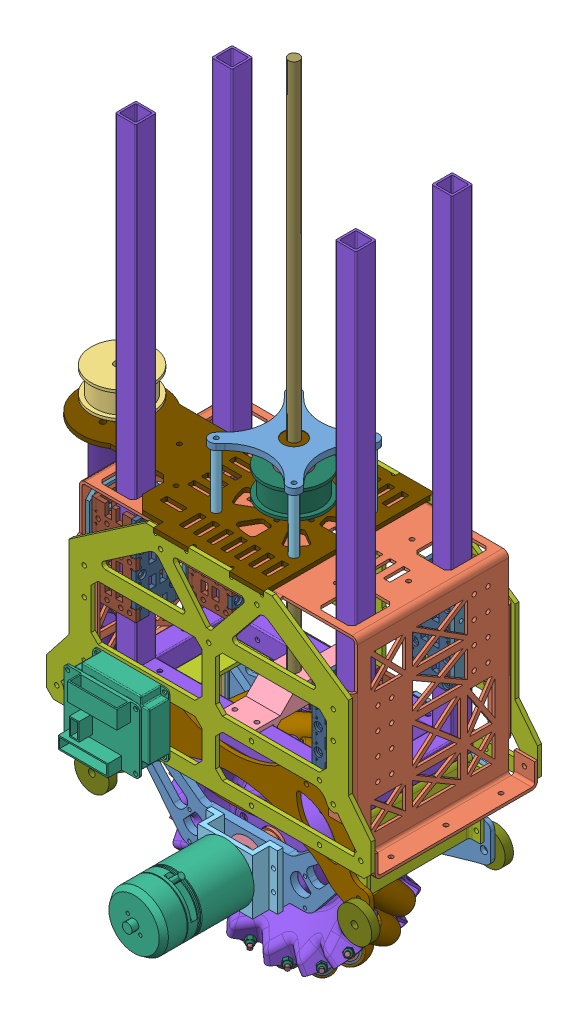
SolidWorks assembly 轮子模块 the other side, configuration 默认. Lengths in mm.
Overall size (273 598.21 183.3).
223 component instances, 37 part files, 118 mates.
Components (placement in the parent):
- 轮子固定铝件-1: 轮子固定铝件 [默认] at (-59.2295 -8.2139 167) size (170 67.5 6)
- 悬挂轮轴-3510（8.0）-1: 悬挂轮轴-3510（8.0） [默认] at (-59.2295 -8.2139 228.5) x (-0.707107 -0.707107 0) z (0 0 -1) size (54 54 80)
- 轮子固定铝件-2: 轮子固定铝件 [默认] at (-59.2295 -8.2139 235) x (-1 0 0) z (0 0 -1) size (170 67.5 6)
- 轮子固定片 连接件-1: 轮子固定片 连接件 [默认] at (104.7705 16.7861 201) x (1 0 0) z (0 1 0) size (7 58 25)
- 法兰轴承15-28-7 （00）-3: 法兰轴承15-28-7 （00） [默认] at (-59.2295 -8.2139 234.5) x (-0.923728 -0.383049 0) z (0 0 -1) size (30.5 30.5 7)
- 法兰轴承15-28-7 （00）-4: 法兰轴承15-28-7 （00） [默认] at (-59.2295 -8.2139 167.5) size (30.5 30.5 7)
- 轮子固定片 连接件-2: 轮子固定片 连接件 [默认] at (-223.2295 16.7861 201) x (-1 0 0) z (0 1 0) size (7 58 25)
- 悬挂-电机架（3510-8.0）-1: 悬挂-电机架（3510-8.0） [默认] at (-59.2295 -28.2139 262.3988) x (1 0 0) z (0 1 0) size (52 16 40)
- 3510无刷电机带减速箱（00）-1: 3510无刷电机带减速箱（00） [默认] at (-59.2295 -8.2139 278.6) x (-0.707107 0.707107 0) z (0.707107 0.707107 0) size (42 98.3 47)
- 轮子固定钣金-1: 轮子固定钣金 [默认] at (-59.2295 61.7861 158.5) size (191 52.5 85)
- 伸缩框架-2.0-（3510）  轻量化（8.0）-1: 伸缩框架-2.0-（3510）  轻量化（8.0） [默认<按加工>] at (-59.2295 71.7861 201) size (193.2 417.5 85)
- 加固碳板-1: 加固碳板 [默认] at (-59.2295 45.5361 243.5) size (201 81.5 3)
- 碳板滑车-1: 碳板滑车 [默认] at (49.0727 115.5126 186.5) size (32 64 32)
  - 碳板长滑车拼接板1-1: 碳板长滑车拼接板1 [默认] at (-28.3022 -33.7153 62.5) size (32 64 3)
  - 碳板长滑车拼接板2-1: 碳板长滑车拼接板2 [默认] at (-12.3022 30.2847 49.5) x (0 0 -1) z (-1 0 0) size (32 64 3)
  - 碳板长滑车拼接板1-2: 碳板长滑车拼接板1 [默认] at (-41.3022 30.2847 49.5) x (0 0 -1) z (-1 0 0) size (32 64 3)
  - 碳板长滑车拼接板2-2: 碳板长滑车拼接板2 [默认] at (-28.3022 -33.7153 33.5) size (32 64 3)
- 碳板滑车-2: 碳板滑车 [默认] at (49.0727 150.5126 116.5) size (32 64 32)
  - 碳板长滑车拼接板1-1: 碳板长滑车拼接板1 [默认] at (-28.3022 -33.7153 62.5) size (32 64 3)
  - 碳板长滑车拼接板2-1: 碳板长滑车拼接板2 [默认] at (-12.3022 30.2847 49.5) x (0 0 -1) z (-1 0 0) size (32 64 3)
  - 碳板长滑车拼接板1-2: 碳板长滑车拼接板1 [默认] at (-41.3022 30.2847 49.5) x (0 0 -1) z (-1 0 0) size (32 64 3)
  - 碳板长滑车拼接板2-2: 碳板长滑车拼接板2 [默认] at (-28.3022 -33.7153 33.5) size (32 64 3)
- 碳板滑车-3: 碳板滑车 [默认] at (-167.5318 115.5126 215.5) x (-1 0 0) z (0 0 -1) size (32 64 32)
  - 碳板长滑车拼接板1-1: 碳板长滑车拼接板1 [默认] at (-28.3022 -33.7153 62.5) size (32 64 3)
  - 碳板长滑车拼接板2-1: 碳板长滑车拼接板2 [默认] at (-12.3022 30.2847 49.5) x (0 0 -1) z (-1 0 0) size (32 64 3)
  - 碳板长滑车拼接板1-2: 碳板长滑车拼接板1 [默认] at (-41.3022 30.2847 49.5) x (0 0 -1) z (-1 0 0) size (32 64 3)
  - 碳板长滑车拼接板2-2: 碳板长滑车拼接板2 [默认] at (-28.3022 -33.7153 33.5) size (32 64 3)
- 碳板滑车-4: 碳板滑车 [默认] at (-188.7295 147.0821 264.3022) x (0 0 1) z (1 0 0) size (32 64 32)
  - 碳板长滑车拼接板1-1: 碳板长滑车拼接板1 [默认] at (-28.3022 -33.7153 62.5) size (32 64 3)
  - 碳板长滑车拼接板2-1: 碳板长滑车拼接板2 [默认] at (-12.3022 30.2847 49.5) x (0 0 -1) z (-1 0 0) size (32 64 3)
  - 碳板长滑车拼接板1-2: 碳板长滑车拼接板1 [默认] at (-41.3022 30.2847 49.5) x (0 0 -1) z (-1 0 0) size (32 64 3)
  - 碳板长滑车拼接板2-2: 碳板长滑车拼接板2 [默认] at (-28.3022 -33.7153 33.5) size (32 64 3)
- T8-300丝杆-1: T8-300丝杆 [默认] at (-59.2295 79.2861 201) x (-0.352036 0 -0.935986) z (0.935986 0 -0.352036) size (8 400 8)
- CBHG丝杆螺母-内8mm-1: CBHG丝杆螺母-内8mm [默认] at (-59.2295 226.2973 201) x (-0.096242 0 -0.995358) z (-0.995358 0 0.096242) size (22 16.5 22)
- 碳板垫片-1: 碳板垫片 [默认] at (36.7705 117.7973 236) x (0 0 -1) z (1 0 0) size (35 60 3)
- 碳板垫片-2: 碳板垫片 [默认] at (-155.2295 152.7973 236) x (0 0 1) z (-1 0 0) size (35 60 3)
- 碳板垫片-3: 碳板垫片 [默认] at (-155.2295 117.7973 166) x (0 0 1) z (-1 0 0) size (35 60 3)
- 碳板垫片-4: 碳板垫片 [默认] at (36.7705 152.7973 166) x (0 0 -1) z (1 0 0) size (35 60 3)
- M5 25齿 同步轮-1: M5 25齿 同步轮 [默认] at (-59.2295 221.2973 201) x (0.096242 0 0.995358) z (0.995358 0 -0.096242) size (45 20 45)
- 内径10外20厚5-1: 内径10外20厚5 [默认] at (-59.2295 203.2973 201) x (0.98727 0 0.159053) z (-0.159053 0 0.98727) size (19 5 19)
- 毒升电机-1: 毒升电机 [默认] at (-184.2295 143.6973 201) x (1 0 0) z (0 1 0) size (35 42.5 158.6)
- 688 ZZ 轴承-1: 688 ZZ 轴承 [默认] at (-59.2295 239.2973 201) x (-0.805456 0 -0.592655) z (-0.592655 0 0.805456) size (18 5 18)
- 同步带限位铝件3-1: 同步带限位铝件3 [默认] at (-59.2295 240.2973 201) x (0 0 1) z (1 0 0) size (66.57 4.5 66.57)
- 轮子模块定位固定钣金-1: 轮子模块定位固定钣金 [默认] at (-59.2295 189.2973 146) size (236 142 118)
- M5 25齿 同步轮（电机用）-1: M5 25齿 同步轮（电机用） [默认] at (-184.2295 205.2973 201) x (-1 0 0) z (0 0 -1) size (45 20 45)
- 丝杆末端定位铝件-1: 丝杆末端定位铝件 [默认] at (-46.7295 82.2861 201) x (0 0 1) z (-1 0 0) size (85 25 25)
- 41.5mm铝棒-1: 41.5mm铝棒 [默认] at (-30.9453 194.2973 229.2843) x (-0.695799 0 0.718237) z (-0.718237 0 -0.695799) size (6 41 6)
- 41.5mm铝棒-2: 41.5mm铝棒 [默认] at (-87.5138 194.2973 172.7157) size (6 41 6)
- 41.5mm铝棒-3: 41.5mm铝棒 [默认] at (-87.5138 194.2973 229.2843) size (6 41 6)
- 41.5mm铝棒-4: 41.5mm铝棒 [默认] at (-30.9453 194.2973 172.7157) x (0.902918 0 -0.429812) z (0.429812 0 0.902918) size (6 41 6)
- 毒升电机电调-1: 毒升电机电调 [默认] at (-115.0295 75.1473 263) x (-1 0 0) z (0 0 1) size (55 46.3 32)
- 钣金加固碳板侧面-1: 钣金加固碳板侧面 [默认] at (-59.2295 183.2973 260) size (236 144.5 3)
- 钣金加固碳板侧面-2: 钣金加固碳板侧面 [默认] at (-59.2295 183.2973 139) size (236 144.5 3)
- 麦轮组装左-1: 麦轮组装左 [默认] at (-42.3506 -22.7788 70.6482) x (0.935906 -0.35225 0) z (0 0 1) size (168 168 53.18)
  - 麦轮钣金-1: 麦轮钣金 [默认] at (-20.9276 7.6858 132.4522) size (142.88 142.88 24.05)
  - 麦轮钣金-2: 麦轮钣金 [默认] at (-20.9276 7.6858 129.2518) x (-0.980785 -0.19509 0) z (0 0 -1) size (142.88 142.88 24.05)
  - 滚花橡胶轮组装-1: 滚花橡胶轮组装 [默认] at (60.4121 -1.9858 154.8754) x (0.932849 -0.320965 -0.163627) z (-0.338043 -0.622763 -0.705615) size (18.5 18.5 53)
    - 滚花橡胶轮外-1: 滚花橡胶轮外 [默认] at (-9.896 1.7835 38.5971) size (18.5 18.5 38)
    - 滚花铝柱-1: 滚花铝柱 [默认] at (-9.896 1.7835 38) x (0.787441 0.61639 0) z (-0.61639 0.787441 0) size (13 38 13)
    - 轴承5X10X4-1: 轴承5X10X4 [默认] at (-9.896 1.7835 55) x (0.442498 0.896769 0) z (-0.896769 0.442498 0) size (10 4 10)
    - 轴承5X10X4-2: 轴承5X10X4 [默认] at (-9.896 1.7835 21) x (0.442498 0.896769 0) z (-0.896769 0.442498 0) size (10 4 10)
    - 铜管3X5-1: 铜管3X5 [默认] at (-9.896 1.7835 38) x (0.823254 0.567673 0) z (-0.567673 0.823254 0) size (5 38 5)
    - 螺丝-1: 螺丝 [默认] at (-9.896 1.7835 59.6) x (-0.462621 0.886556 0) z (0 0 1) size (5.5 5.5 53)
    - 垫片-1: 垫片 [默认] at (-9.896 1.7835 57) x (1 0 0) z (0 -1 0) size (7 0.8 7)
    - 垫片-2: 垫片 [默认] at (-9.896 1.7835 19) x (0.746862 -0.664979 0) z (0.664979 0.746862 0) size (7 0.8 7)
    - 螺母-1: 螺母 [默认] at (-9.896 1.7835 16.2) x (-0.766894 0.641774 0) z (0 0 -1) size (6.35 5.5 4.25)
  - 滚花橡胶轮组装-2: 滚花橡胶轮组装 [默认] at (57.9216 29.8777 154.8754) x (0.984668 0.060453 -0.163627) z (-0.073989 -0.704722 -0.705615) size (18.5 18.5 53)
    - 滚花橡胶轮外-1: 滚花橡胶轮外 [默认] at (-9.896 1.7835 38.5971) size (18.5 18.5 38)
    - 滚花铝柱-1: 滚花铝柱 [默认] at (-9.896 1.7835 38) x (0.787441 0.61639 0) z (-0.61639 0.787441 0) size (13 38 13)
    - 轴承5X10X4-1: 轴承5X10X4 [默认] at (-9.896 1.7835 55) x (0.442498 0.896769 0) z (-0.896769 0.442498 0) size (10 4 10)
    - 轴承5X10X4-2: 轴承5X10X4 [默认] at (-9.896 1.7835 21) x (0.442498 0.896769 0) z (-0.896769 0.442498 0) size (10 4 10)
    - 铜管3X5-1: 铜管3X5 [默认] at (-9.896 1.7835 38) x (0.823254 0.567673 0) z (-0.567673 0.823254 0) size (5 38 5)
    - 螺丝-1: 螺丝 [默认] at (-9.896 1.7835 59.6) x (-0.462621 0.886556 0) z (0 0 1) size (5.5 5.5 53)
    - 垫片-1: 垫片 [默认] at (-9.896 1.7835 57) x (1 0 0) z (0 -1 0) size (7 0.8 7)
    - 垫片-2: 垫片 [默认] at (-9.896 1.7835 19) x (0.746862 -0.664979 0) z (0.664979 0.746862 0) size (7 0.8 7)
    - 螺母-1: 螺母 [默认] at (-9.896 1.7835 16.2) x (-0.766894 0.641774 0) z (0 0 -1) size (6.35 5.5 4.25)
  - 滚花橡胶轮组装-3: 滚花橡胶轮组装 [默认] at (43.4271 58.3628 154.8754) x (0.88658 0.432668 -0.163627) z (0.201328 -0.679392 -0.705615) size (18.5 18.5 53)
    - 滚花橡胶轮外-1: 滚花橡胶轮外 [默认] at (-9.896 1.7835 38.5971) size (18.5 18.5 38)
    - 滚花铝柱-1: 滚花铝柱 [默认] at (-9.896 1.7835 38) x (0.787441 0.61639 0) z (-0.61639 0.787441 0) size (13 38 13)
    - 轴承5X10X4-1: 轴承5X10X4 [默认] at (-9.896 1.7835 55) x (0.442498 0.896769 0) z (-0.896769 0.442498 0) size (10 4 10)
    - 轴承5X10X4-2: 轴承5X10X4 [默认] at (-9.896 1.7835 21) x (0.442498 0.896769 0) z (-0.896769 0.442498 0) size (10 4 10)
    - 铜管3X5-1: 铜管3X5 [默认] at (-9.896 1.7835 38) x (0.823254 0.567673 0) z (-0.567673 0.823254 0) size (5 38 5)
    - 螺丝-1: 螺丝 [默认] at (-9.896 1.7835 59.6) x (-0.462621 0.886556 0) z (0 0 1) size (5.5 5.5 53)
    - 垫片-1: 垫片 [默认] at (-9.896 1.7835 57) x (1 0 0) z (0 -1 0) size (7 0.8 7)
    - 垫片-2: 垫片 [默认] at (-9.896 1.7835 19) x (0.746862 -0.664979 0) z (0.664979 0.746862 0) size (7 0.8 7)
    - 螺母-1: 螺母 [默认] at (-9.896 1.7835 16.2) x (-0.766894 0.641774 0) z (0 0 -1) size (6.35 5.5 4.25)
  - 滚花橡胶轮组装-4: 滚花橡胶轮组装 [默认] at (19.1352 79.1327 154.8754) x (0.653519 0.739013 -0.163627) z (0.445995 -0.550632 -0.705615) size (18.5 18.5 53)
    - 滚花橡胶轮外-1: 滚花橡胶轮外 [默认] at (-9.896 1.7835 38.5971) size (18.5 18.5 38)
    - 滚花铝柱-1: 滚花铝柱 [默认] at (-9.896 1.7835 38) x (0.787441 0.61639 0) z (-0.61639 0.787441 0) size (13 38 13)
    - 轴承5X10X4-1: 轴承5X10X4 [默认] at (-9.896 1.7835 55) x (0.442498 0.896769 0) z (-0.896769 0.442498 0) size (10 4 10)
    - 轴承5X10X4-2: 轴承5X10X4 [默认] at (-9.896 1.7835 21) x (0.442498 0.896769 0) z (-0.896769 0.442498 0) size (10 4 10)
    - 铜管3X5-1: 铜管3X5 [默认] at (-9.896 1.7835 38) x (0.823254 0.567673 0) z (-0.567673 0.823254 0) size (5 38 5)
    - 螺丝-1: 螺丝 [默认] at (-9.896 1.7835 59.6) x (-0.462621 0.886556 0) z (0 0 1) size (5.5 5.5 53)
    - 垫片-1: 垫片 [默认] at (-9.896 1.7835 57) x (1 0 0) z (0 -1 0) size (7 0.8 7)
    - 垫片-2: 垫片 [默认] at (-9.896 1.7835 19) x (0.746862 -0.664979 0) z (0.664979 0.746862 0) size (7 0.8 7)
    - 螺母-1: 螺母 [默认] at (-9.896 1.7835 16.2) x (-0.766894 0.641774 0) z (0 0 -1) size (6.35 5.5 4.25)
  - 滚花橡胶轮组装-5: 滚花橡胶轮组装 [默认] at (-11.256 89.0255 154.8754) x (0.320965 0.932849 -0.163627) z (0.622763 -0.338043 -0.705615) size (18.5 18.5 53)
    - 滚花橡胶轮外-1: 滚花橡胶轮外 [默认] at (-9.896 1.7835 38.5971) size (18.5 18.5 38)
    - 滚花铝柱-1: 滚花铝柱 [默认] at (-9.896 1.7835 38) x (0.787441 0.61639 0) z (-0.61639 0.787441 0) size (13 38 13)
    - 轴承5X10X4-1: 轴承5X10X4 [默认] at (-9.896 1.7835 55) x (0.442498 0.896769 0) z (-0.896769 0.442498 0) size (10 4 10)
    - 轴承5X10X4-2: 轴承5X10X4 [默认] at (-9.896 1.7835 21) x (0.442498 0.896769 0) z (-0.896769 0.442498 0) size (10 4 10)
    - 铜管3X5-1: 铜管3X5 [默认] at (-9.896 1.7835 38) x (0.823254 0.567673 0) z (-0.567673 0.823254 0) size (5 38 5)
    - 螺丝-1: 螺丝 [默认] at (-9.896 1.7835 59.6) x (-0.462621 0.886556 0) z (0 0 1) size (5.5 5.5 53)
    - 垫片-1: 垫片 [默认] at (-9.896 1.7835 57) x (1 0 0) z (0 -1 0) size (7 0.8 7)
    - 垫片-2: 垫片 [默认] at (-9.896 1.7835 19) x (0.746862 -0.664979 0) z (0.664979 0.746862 0) size (7 0.8 7)
    - 螺母-1: 螺母 [默认] at (-9.896 1.7835 16.2) x (-0.766894 0.641774 0) z (0 0 -1) size (6.35 5.5 4.25)
  - 滚花橡胶轮组装-6: 滚花橡胶轮组装 [默认] at (-43.1195 86.535 154.8754) x (-0.060453 0.984668 -0.163627) z (0.704722 -0.073989 -0.705615) size (18.5 18.5 53)
    - 滚花橡胶轮外-1: 滚花橡胶轮外 [默认] at (-9.896 1.7835 38.5971) size (18.5 18.5 38)
    - 滚花铝柱-1: 滚花铝柱 [默认] at (-9.896 1.7835 38) x (0.787441 0.61639 0) z (-0.61639 0.787441 0) size (13 38 13)
    - 轴承5X10X4-1: 轴承5X10X4 [默认] at (-9.896 1.7835 55) x (0.442498 0.896769 0) z (-0.896769 0.442498 0) size (10 4 10)
    - 轴承5X10X4-2: 轴承5X10X4 [默认] at (-9.896 1.7835 21) x (0.442498 0.896769 0) z (-0.896769 0.442498 0) size (10 4 10)
    - 铜管3X5-1: 铜管3X5 [默认] at (-9.896 1.7835 38) x (0.823254 0.567673 0) z (-0.567673 0.823254 0) size (5 38 5)
    - 螺丝-1: 螺丝 [默认] at (-9.896 1.7835 59.6) x (-0.462621 0.886556 0) z (0 0 1) size (5.5 5.5 53)
    - 垫片-1: 垫片 [默认] at (-9.896 1.7835 57) x (1 0 0) z (0 -1 0) size (7 0.8 7)
    - 垫片-2: 垫片 [默认] at (-9.896 1.7835 19) x (0.746862 -0.664979 0) z (0.664979 0.746862 0) size (7 0.8 7)
    - 螺母-1: 螺母 [默认] at (-9.896 1.7835 16.2) x (-0.766894 0.641774 0) z (0 0 -1) size (6.35 5.5 4.25)
  - 滚花橡胶轮组装-7: 滚花橡胶轮组装 [默认] at (-71.6045 72.0405 154.8754) x (-0.432668 0.88658 -0.163627) z (0.679392 0.201328 -0.705615) size (18.5 18.5 53)
    - 滚花橡胶轮外-1: 滚花橡胶轮外 [默认] at (-9.896 1.7835 38.5971) size (18.5 18.5 38)
    - 滚花铝柱-1: 滚花铝柱 [默认] at (-9.896 1.7835 38) x (0.787441 0.61639 0) z (-0.61639 0.787441 0) size (13 38 13)
    - 轴承5X10X4-1: 轴承5X10X4 [默认] at (-9.896 1.7835 55) x (0.442498 0.896769 0) z (-0.896769 0.442498 0) size (10 4 10)
    - 轴承5X10X4-2: 轴承5X10X4 [默认] at (-9.896 1.7835 21) x (0.442498 0.896769 0) z (-0.896769 0.442498 0) size (10 4 10)
    - 铜管3X5-1: 铜管3X5 [默认] at (-9.896 1.7835 38) x (0.823254 0.567673 0) z (-0.567673 0.823254 0) size (5 38 5)
    - 螺丝-1: 螺丝 [默认] at (-9.896 1.7835 59.6) x (-0.462621 0.886556 0) z (0 0 1) size (5.5 5.5 53)
    - 垫片-1: 垫片 [默认] at (-9.896 1.7835 57) x (1 0 0) z (0 -1 0) size (7 0.8 7)
    - 垫片-2: 垫片 [默认] at (-9.896 1.7835 19) x (0.746862 -0.664979 0) z (0.664979 0.746862 0) size (7 0.8 7)
    - 螺母-1: 螺母 [默认] at (-9.896 1.7835 16.2) x (-0.766894 0.641774 0) z (0 0 -1) size (6.35 5.5 4.25)
  - 滚花橡胶轮组装-8: 滚花橡胶轮组装 [默认] at (-92.3745 47.7486 154.8754) x (-0.739013 0.653519 -0.163627) z (0.550632 0.445995 -0.705615) size (18.5 18.5 53)
    - 滚花橡胶轮外-1: 滚花橡胶轮外 [默认] at (-9.896 1.7835 38.5971) size (18.5 18.5 38)
    - 滚花铝柱-1: 滚花铝柱 [默认] at (-9.896 1.7835 38) x (0.787441 0.61639 0) z (-0.61639 0.787441 0) size (13 38 13)
    - 轴承5X10X4-1: 轴承5X10X4 [默认] at (-9.896 1.7835 55) x (0.442498 0.896769 0) z (-0.896769 0.442498 0) size (10 4 10)
    - 轴承5X10X4-2: 轴承5X10X4 [默认] at (-9.896 1.7835 21) x (0.442498 0.896769 0) z (-0.896769 0.442498 0) size (10 4 10)
    - 铜管3X5-1: 铜管3X5 [默认] at (-9.896 1.7835 38) x (0.823254 0.567673 0) z (-0.567673 0.823254 0) size (5 38 5)
    - 螺丝-1: 螺丝 [默认] at (-9.896 1.7835 59.6) x (-0.462621 0.886556 0) z (0 0 1) size (5.5 5.5 53)
    - 垫片-1: 垫片 [默认] at (-9.896 1.7835 57) x (1 0 0) z (0 -1 0) size (7 0.8 7)
    - 垫片-2: 垫片 [默认] at (-9.896 1.7835 19) x (0.746862 -0.664979 0) z (0.664979 0.746862 0) size (7 0.8 7)
    - 螺母-1: 螺母 [默认] at (-9.896 1.7835 16.2) x (-0.766894 0.641774 0) z (0 0 -1) size (6.35 5.5 4.25)
  - 滚花橡胶轮组装-9: 滚花橡胶轮组装 [默认] at (-102.2673 17.3574 154.8754) x (-0.932849 0.320965 -0.163627) z (0.338043 0.622763 -0.705615) size (18.5 18.5 53)
    - 滚花橡胶轮外-1: 滚花橡胶轮外 [默认] at (-9.896 1.7835 38.5971) size (18.5 18.5 38)
    - 滚花铝柱-1: 滚花铝柱 [默认] at (-9.896 1.7835 38) x (0.787441 0.61639 0) z (-0.61639 0.787441 0) size (13 38 13)
    - 轴承5X10X4-1: 轴承5X10X4 [默认] at (-9.896 1.7835 55) x (0.442498 0.896769 0) z (-0.896769 0.442498 0) size (10 4 10)
    - 轴承5X10X4-2: 轴承5X10X4 [默认] at (-9.896 1.7835 21) x (0.442498 0.896769 0) z (-0.896769 0.442498 0) size (10 4 10)
    - 铜管3X5-1: 铜管3X5 [默认] at (-9.896 1.7835 38) x (0.823254 0.567673 0) z (-0.567673 0.823254 0) size (5 38 5)
    - 螺丝-1: 螺丝 [默认] at (-9.896 1.7835 59.6) x (-0.462621 0.886556 0) z (0 0 1) size (5.5 5.5 53)
    - 垫片-1: 垫片 [默认] at (-9.896 1.7835 57) x (1 0 0) z (0 -1 0) size (7 0.8 7)
    - 垫片-2: 垫片 [默认] at (-9.896 1.7835 19) x (0.746862 -0.664979 0) z (0.664979 0.746862 0) size (7 0.8 7)
    - 螺母-1: 螺母 [默认] at (-9.896 1.7835 16.2) x (-0.766894 0.641774 0) z (0 0 -1) size (6.35 5.5 4.25)
  - 滚花橡胶轮组装-10: 滚花橡胶轮组装 [默认] at (-99.7768 -14.5061 154.8754) x (-0.984668 -0.060453 -0.163627) z (0.073989 0.704722 -0.705615) size (18.5 18.5 53)
    - 滚花橡胶轮外-1: 滚花橡胶轮外 [默认] at (-9.896 1.7835 38.5971) size (18.5 18.5 38)
    - 滚花铝柱-1: 滚花铝柱 [默认] at (-9.896 1.7835 38) x (0.787441 0.61639 0) z (-0.61639 0.787441 0) size (13 38 13)
    - 轴承5X10X4-1: 轴承5X10X4 [默认] at (-9.896 1.7835 55) x (0.442498 0.896769 0) z (-0.896769 0.442498 0) size (10 4 10)
    - 轴承5X10X4-2: 轴承5X10X4 [默认] at (-9.896 1.7835 21) x (0.442498 0.896769 0) z (-0.896769 0.442498 0) size (10 4 10)
    - 铜管3X5-1: 铜管3X5 [默认] at (-9.896 1.7835 38) x (0.823254 0.567673 0) z (-0.567673 0.823254 0) size (5 38 5)
    - 螺丝-1: 螺丝 [默认] at (-9.896 1.7835 59.6) x (-0.462621 0.886556 0) z (0 0 1) size (5.5 5.5 53)
    - 垫片-1: 垫片 [默认] at (-9.896 1.7835 57) x (1 0 0) z (0 -1 0) size (7 0.8 7)
    - 垫片-2: 垫片 [默认] at (-9.896 1.7835 19) x (0.746862 -0.664979 0) z (0.664979 0.746862 0) size (7 0.8 7)
    - 螺母-1: 螺母 [默认] at (-9.896 1.7835 16.2) x (-0.766894 0.641774 0) z (0 0 -1) size (6.35 5.5 4.25)
  - 滚花橡胶轮组装-11: 滚花橡胶轮组装 [默认] at (-85.2823 -42.9912 154.8754) x (-0.88658 -0.432668 -0.163627) z (-0.201328 0.679392 -0.705615) size (18.5 18.5 53)
    - 滚花橡胶轮外-1: 滚花橡胶轮外 [默认] at (-9.896 1.7835 38.5971) size (18.5 18.5 38)
    - 滚花铝柱-1: 滚花铝柱 [默认] at (-9.896 1.7835 38) x (0.787441 0.61639 0) z (-0.61639 0.787441 0) size (13 38 13)
    - 轴承5X10X4-1: 轴承5X10X4 [默认] at (-9.896 1.7835 55) x (0.442498 0.896769 0) z (-0.896769 0.442498 0) size (10 4 10)
    - 轴承5X10X4-2: 轴承5X10X4 [默认] at (-9.896 1.7835 21) x (0.442498 0.896769 0) z (-0.896769 0.442498 0) size (10 4 10)
    - 铜管3X5-1: 铜管3X5 [默认] at (-9.896 1.7835 38) x (0.823254 0.567673 0) z (-0.567673 0.823254 0) size (5 38 5)
    - 螺丝-1: 螺丝 [默认] at (-9.896 1.7835 59.6) x (-0.462621 0.886556 0) z (0 0 1) size (5.5 5.5 53)
    - 垫片-1: 垫片 [默认] at (-9.896 1.7835 57) x (1 0 0) z (0 -1 0) size (7 0.8 7)
    - 垫片-2: 垫片 [默认] at (-9.896 1.7835 19) x (0.746862 -0.664979 0) z (0.664979 0.746862 0) size (7 0.8 7)
    - 螺母-1: 螺母 [默认] at (-9.896 1.7835 16.2) x (-0.766894 0.641774 0) z (0 0 -1) size (6.35 5.5 4.25)
  - 滚花橡胶轮组装-12: 滚花橡胶轮组装 [默认] at (-60.9904 -63.7611 154.8754) x (-0.653519 -0.739013 -0.163627) z (-0.445995 0.550632 -0.705615) size (18.5 18.5 53)
    - 滚花橡胶轮外-1: 滚花橡胶轮外 [默认] at (-9.896 1.7835 38.5971) size (18.5 18.5 38)
    - 滚花铝柱-1: 滚花铝柱 [默认] at (-9.896 1.7835 38) x (0.787441 0.61639 0) z (-0.61639 0.787441 0) size (13 38 13)
    - 轴承5X10X4-1: 轴承5X10X4 [默认] at (-9.896 1.7835 55) x (0.442498 0.896769 0) z (-0.896769 0.442498 0) size (10 4 10)
    - 轴承5X10X4-2: 轴承5X10X4 [默认] at (-9.896 1.7835 21) x (0.442498 0.896769 0) z (-0.896769 0.442498 0) size (10 4 10)
    - 铜管3X5-1: 铜管3X5 [默认] at (-9.896 1.7835 38) x (0.823254 0.567673 0) z (-0.567673 0.823254 0) size (5 38 5)
    - 螺丝-1: 螺丝 [默认] at (-9.896 1.7835 59.6) x (-0.462621 0.886556 0) z (0 0 1) size (5.5 5.5 53)
    - 垫片-1: 垫片 [默认] at (-9.896 1.7835 57) x (1 0 0) z (0 -1 0) size (7 0.8 7)
    - 垫片-2: 垫片 [默认] at (-9.896 1.7835 19) x (0.746862 -0.664979 0) z (0.664979 0.746862 0) size (7 0.8 7)
    - 螺母-1: 螺母 [默认] at (-9.896 1.7835 16.2) x (-0.766894 0.641774 0) z (0 0 -1) size (6.35 5.5 4.25)
  - 滚花橡胶轮组装-13: 滚花橡胶轮组装 [默认] at (-30.5992 -73.6539 154.8754) x (-0.320965 -0.932849 -0.163627) z (-0.622763 0.338043 -0.705615) size (18.5 18.5 53)
    - 滚花橡胶轮外-1: 滚花橡胶轮外 [默认] at (-9.896 1.7835 38.5971) size (18.5 18.5 38)
    - 滚花铝柱-1: 滚花铝柱 [默认] at (-9.896 1.7835 38) x (0.787441 0.61639 0) z (-0.61639 0.787441 0) size (13 38 13)
    - 轴承5X10X4-1: 轴承5X10X4 [默认] at (-9.896 1.7835 55) x (0.442498 0.896769 0) z (-0.896769 0.442498 0) size (10 4 10)
    - 轴承5X10X4-2: 轴承5X10X4 [默认] at (-9.896 1.7835 21) x (0.442498 0.896769 0) z (-0.896769 0.442498 0) size (10 4 10)
    - 铜管3X5-1: 铜管3X5 [默认] at (-9.896 1.7835 38) x (0.823254 0.567673 0) z (-0.567673 0.823254 0) size (5 38 5)
    - 螺丝-1: 螺丝 [默认] at (-9.896 1.7835 59.6) x (-0.462621 0.886556 0) z (0 0 1) size (5.5 5.5 53)
    - 垫片-1: 垫片 [默认] at (-9.896 1.7835 57) x (1 0 0) z (0 -1 0) size (7 0.8 7)
    - 垫片-2: 垫片 [默认] at (-9.896 1.7835 19) x (0.746862 -0.664979 0) z (0.664979 0.746862 0) size (7 0.8 7)
    - 螺母-1: 螺母 [默认] at (-9.896 1.7835 16.2) x (-0.766894 0.641774 0) z (0 0 -1) size (6.35 5.5 4.25)
  - 滚花橡胶轮组装-14: 滚花橡胶轮组装 [默认] at (1.2643 -71.1634 154.8754) x (0.060453 -0.984668 -0.163627) z (-0.704722 0.073989 -0.705615) size (18.5 18.5 53)
    - 滚花橡胶轮外-1: 滚花橡胶轮外 [默认] at (-9.896 1.7835 38.5971) size (18.5 18.5 38)
    - 滚花铝柱-1: 滚花铝柱 [默认] at (-9.896 1.7835 38) x (0.787441 0.61639 0) z (-0.61639 0.787441 0) size (13 38 13)
    - 轴承5X10X4-1: 轴承5X10X4 [默认] at (-9.896 1.7835 55) x (0.442498 0.896769 0) z (-0.896769 0.442498 0) size (10 4 10)
    - 轴承5X10X4-2: 轴承5X10X4 [默认] at (-9.896 1.7835 21) x (0.442498 0.896769 0) z (-0.896769 0.442498 0) size (10 4 10)
    - 铜管3X5-1: 铜管3X5 [默认] at (-9.896 1.7835 38) x (0.823254 0.567673 0) z (-0.567673 0.823254 0) size (5 38 5)
    - 螺丝-1: 螺丝 [默认] at (-9.896 1.7835 59.6) x (-0.462621 0.886556 0) z (0 0 1) size (5.5 5.5 53)
    - 垫片-1: 垫片 [默认] at (-9.896 1.7835 57) x (1 0 0) z (0 -1 0) size (7 0.8 7)
    - 垫片-2: 垫片 [默认] at (-9.896 1.7835 19) x (0.746862 -0.664979 0) z (0.664979 0.746862 0) size (7 0.8 7)
    - 螺母-1: 螺母 [默认] at (-9.896 1.7835 16.2) x (-0.766894 0.641774 0) z (0 0 -1) size (6.35 5.5 4.25)
  - 滚花橡胶轮组装-15: 滚花橡胶轮组装 [默认] at (29.7494 -56.6689 154.8754) x (0.432668 -0.88658 -0.163627) z (-0.679392 -0.201328 -0.705615) size (18.5 18.5 53)
    - 滚花橡胶轮外-1: 滚花橡胶轮外 [默认] at (-9.896 1.7835 38.5971) size (18.5 18.5 38)
    - 滚花铝柱-1: 滚花铝柱 [默认] at (-9.896 1.7835 38) x (0.787441 0.61639 0) z (-0.61639 0.787441 0) size (13 38 13)
    - 轴承5X10X4-1: 轴承5X10X4 [默认] at (-9.896 1.7835 55) x (0.442498 0.896769 0) z (-0.896769 0.442498 0) size (10 4 10)
    - 轴承5X10X4-2: 轴承5X10X4 [默认] at (-9.896 1.7835 21) x (0.442498 0.896769 0) z (-0.896769 0.442498 0) size (10 4 10)
    - 铜管3X5-1: 铜管3X5 [默认] at (-9.896 1.7835 38) x (0.823254 0.567673 0) z (-0.567673 0.823254 0) size (5 38 5)
    - 螺丝-1: 螺丝 [默认] at (-9.896 1.7835 59.6) x (-0.462621 0.886556 0) z (0 0 1) size (5.5 5.5 53)
    - 垫片-1: 垫片 [默认] at (-9.896 1.7835 57) x (1 0 0) z (0 -1 0) size (7 0.8 7)
    - 垫片-2: 垫片 [默认] at (-9.896 1.7835 19) x (0.746862 -0.664979 0) z (0.664979 0.746862 0) size (7 0.8 7)
    - 螺母-1: 螺母 [默认] at (-9.896 1.7835 16.2) x (-0.766894 0.641774 0) z (0 0 -1) size (6.35 5.5 4.25)
  - 滚花橡胶轮组装-16: 滚花橡胶轮组装 [默认] at (50.5193 -32.377 154.8754) x (0.739013 -0.653519 -0.163627) z (-0.550632 -0.445995 -0.705615) size (18.5 18.5 53)
    - 滚花橡胶轮外-1: 滚花橡胶轮外 [默认] at (-9.896 1.7835 38.5971) size (18.5 18.5 38)
    - 滚花铝柱-1: 滚花铝柱 [默认] at (-9.896 1.7835 38) x (0.787441 0.61639 0) z (-0.61639 0.787441 0) size (13 38 13)
    - 轴承5X10X4-1: 轴承5X10X4 [默认] at (-9.896 1.7835 55) x (0.442498 0.896769 0) z (-0.896769 0.442498 0) size (10 4 10)
    - 轴承5X10X4-2: 轴承5X10X4 [默认] at (-9.896 1.7835 21) x (0.442498 0.896769 0) z (-0.896769 0.442498 0) size (10 4 10)
    - 铜管3X5-1: 铜管3X5 [默认] at (-9.896 1.7835 38) x (0.823254 0.567673 0) z (-0.567673 0.823254 0) size (5 38 5)
    - 螺丝-1: 螺丝 [默认] at (-9.896 1.7835 59.6) x (-0.462621 0.886556 0) z (0 0 1) size (5.5 5.5 53)
    - 垫片-1: 垫片 [默认] at (-9.896 1.7835 57) x (1 0 0) z (0 -1 0) size (7 0.8 7)
    - 垫片-2: 垫片 [默认] at (-9.896 1.7835 19) x (0.746862 -0.664979 0) z (0.664979 0.746862 0) size (7 0.8 7)
    - 螺母-1: 螺母 [默认] at (-9.896 1.7835 16.2) x (-0.766894 0.641774 0) z (0 0 -1) size (6.35 5.5 4.25)
- 支撑轴承-1: 支撑轴承 [默认] at (36.2705 6.7861 149.5) x (1 0 0) z (0 -1 0) size (25 6 25)
- 支撑轴承-2: 支撑轴承 [默认] at (36.2705 6.7861 246.5) x (1 0 0) z (0 -1 0) size (25 6 25)
- 支撑轴承-3: 支撑轴承 [默认] at (-154.7295 6.7861 149.5) x (0.99848 -0.055119 0) z (-0.055119 -0.99848 0) size (25 6 25)
- 支撑轴承-4: 支撑轴承 [默认] at (-154.7295 6.7861 246.5) x (1 0 0) z (0 -1 0) size (25 6 25)
- 同步轮垫片-1: 同步轮垫片 [默认] at (-184.2295 197.2973 201) x (-1 0 0) z (0 0 -1) size (20 6 20)
- 电机固定板(转90°)-1: 电机固定板(转90°) [默认] at (-59.2295 191.2973 253.5) x (0 0 1) z (-1 0 0) size (124 3 195)
- 加固碳板 侧面改版-1: 加固碳板 侧面改版 [默认] at (-59.2295 45.5361 155.5) size (201 98.17 3)
Mates (geometry in assembly coordinates):
- 重合5: coincident: plane of 轮子固定铝件-1 through (-144.2295 16.7861 172) normal (-1 0 0); plane of 轮子固定铝件-2 through (-144.2295 16.7861 230) normal (-1 0 0)
- 重合6: coincident: plane of 轮子固定铝件-1 through (-100.4233 -10.7139 172) normal (0 0 1); plane of 轮子固定片 连接件-1 through (18.7705 41.7861 172) normal (0 0 -1)
- 同心8: concentric: cylinder of 悬挂轮轴-3510（8.0）-1 through (-59.2295 -8.2139 244.5) axis (0 0 -1) radius 7.5; cylinder of 法兰轴承15-28-7 （00）-3 through (-59.2295 -8.2139 227.499) axis (0 0 1) radius 7.5
- 重合7: coincident: plane of 轮子固定铝件-2 through (-88.5629 19.2861 229) normal (0 0 -1); plane of 法兰轴承15-28-7 （00）-3 through (-59.2295 -8.2139 229) normal (0 0 1)
- 重合8: coincident: plane of 轮子固定铝件-2 through (-88.5629 19.2861 229) normal (0 0 -1); plane of 法兰轴承15-28-7 （00）-3 through (-59.2295 -8.2139 229) normal (0 0 1)
- 重合9: coincident: plane of 悬挂轮轴-3510（8.0）-1 through (-59.2295 -8.2139 227.5) normal (0 0 1); plane of 法兰轴承15-28-7 （00）-3 through (-59.2295 -8.2139 227.5) normal (0 0 -1)
- 同心9: concentric: cylinder of 轮子固定铝件-2 through (-59.2295 -8.2139 230) axis (0 0 1) radius 14; cylinder of 法兰轴承15-28-7 （00）-3 through (-59.2295 -8.2139 229) axis (0 0 1) radius 14
- 重合10: coincident: plane of 轮子固定铝件-2 through (-18.0358 -10.7139 230) normal (0 0 -1); plane of 轮子固定片 连接件-1 through (25.7705 -18.2139 230) normal (0 0 1)
- 同心10: concentric: cylinder of 轮子固定铝件-1 through (-59.2295 -8.2139 172) axis (0 0 -1) radius 14; cylinder of 法兰轴承15-28-7 （00）-4 through (-59.2295 -8.2139 173) axis (0 0 -1) radius 14
- 同心11: concentric: cylinder of 法兰轴承15-28-7 （00）-4 through (-59.2295 -8.2139 174.501) axis (0 0 -1) radius 7.5; cylinder of 悬挂轮轴-3510（8.0）-1 through (-59.2295 -8.2139 164.5) axis (0 0 1) radius 7.5
- 重合11: coincident: plane of 轮子固定铝件-1 through (-29.8962 19.2861 173) normal (0 0 1); plane of 法兰轴承15-28-7 （00）-4 through (-59.2295 -8.2139 173) normal (0 0 -1)
- 重合12: coincident: circle of 悬挂轮轴-3510（8.0）-1; plane of 法兰轴承15-28-7 （00）-4 through (-59.2295 -8.2139 174.5) normal (0 0 1)
- 重合13: coincident: plane of 轮子固定铝件-2 through (-18.0358 -10.7139 230) normal (0 0 -1); plane of 轮子固定片 连接件-2 through (-137.2295 41.7861 230) normal (0 0 1)
- 重合14: coincident: plane of 轮子固定铝件-2 through (-18.0358 -10.7139 235) normal (0 0 1); plane of 悬挂-电机架（3510-8.0）-1 through (-85.2295 11.7861 235) normal (0 0 -1)
- 同心14: concentric: cylinder of 轮子固定铝件-2 through (-82.2295 -0.7139 229) axis (0 0 -1) radius 1.25; cylinder of 悬挂-电机架（3510-8.0）-1 through (-82.2295 -0.7139 235) axis (0 0 1) radius 1.5
- 同心15: concentric: cylinder of 轮子固定铝件-2 through (-82.2295 -15.7139 229) axis (0 0 -1) radius 1.25; cylinder of 悬挂-电机架（3510-8.0）-1 through (-82.2295 -15.7139 235) axis (0 0 1) radius 1.5
- 同心16: concentric: cylinder of 悬挂-电机架（3510-8.0）-1 through (-59.2295 -8.2139 249.5) axis (0 0 1) radius 13; cylinder of 3510无刷电机带减速箱（00）-1 through (-59.2295 -8.2139 287.3) axis (0 0 1) radius 13
- 同心17: concentric: cylinder of 悬挂轮轴-3510（8.0）-1 through (-59.2295 -8.2139 164.499) axis (0 0 1) radius 5; cylinder of 3510无刷电机带减速箱（00）-1 through (-59.2295 -8.2139 287.3) axis (0 0 1) radius 5
- 平行2: parallel: plane of 悬挂轮轴-3510（8.0）-1 through (-58.4391 -3.2767 164.499) normal (-0.707107 -0.707107 0); plane of 3510无刷电机带减速箱（00）-1 through (-54.2798 -7.5067 244) normal (0.707107 0.707107 0)
- 同心18: concentric: cylinder of 3510无刷电机带减速箱（00）-1 through (-71.6039 4.1605 251) axis (0 0 -1) radius 1.65; cylinder of 悬挂-电机架（3510-8.0）-1 through (-71.6039 4.1605 234.999) axis (0 0 1) radius 2
- 重合17: coincident: plane of 悬挂-电机架（3510-8.0）-1 through (-79.2295 11.7861 251) normal (0 0 1); plane of 3510无刷电机带减速箱（00）-1 through (-68.4219 0.9785 251) normal (0 0 -1)
- 重合24: coincident: plane of 轮子固定片 连接件-1 through (25.7705 14.5501 230) normal (1 0 0); plane of 轮子固定钣金-1 through (25.7705 61.7861 243.5) normal (-1 0 0)
- 重合25: coincident: plane of 轮子固定钣金-1 through (-146.7295 61.7861 243.5) normal (-1 0 0); plane of 伸缩框架-2.0-（3510）  轻量化（8.0）-1 through (-146.7295 78.2861 236) normal (-1 0 0)
- 重合26: coincident: plane of 轮子固定钣金-1 through (-146.7295 59.7861 158.5) normal (0 0 -1); plane of 伸缩框架-2.0-（3510）  轻量化（8.0）-1 through (-139.2295 78.2861 158.5) normal (0 0 -1)
- 重合27: coincident: plane of 轮子固定钣金-1 through (-144.2295 64.2861 243.5) normal (0 1 0); plane of 伸缩框架-2.0-（3510）  轻量化（8.0）-1 through (-139.2295 64.2861 159.5) normal (0 -1 0)
- 重合28: coincident: plane of 轮子固定钣金-1 through (36.2705 11.7861 243.5) normal (0 0 1); plane of 加固碳板-1 through (-59.2295 45.5361 243.5) normal (0 0 -1)
- 宽度2: width: plane of 碳板滑车-2/碳板长滑车拼接板1-1 through (20.7705 116.7973 179) normal (0 0 -1); plane of 碳板滑车-2/碳板长滑车拼接板2-2 through (20.7705 116.7973 153) normal (0 0 1); plane of 伸缩框架-2.0-（3510）  轻量化（8.0）-1 through (14.2705 481.7861 173.5) normal (0 0 1); plane of 伸缩框架-2.0-（3510）  轻量化（8.0）-1 through (14.2705 481.7861 158.5) normal (0 0 -1)
- 宽度3: width: plane of 碳板滑车-2/碳板长滑车拼接板1-2 through (7.7705 180.7973 166) normal (1 0 0); plane of 碳板滑车-2/碳板长滑车拼接板2-1 through (33.7705 180.7973 166) normal (-1 0 0); plane of 伸缩框架-2.0-（3510）  轻量化（8.0）-1 through (13.2705 481.7861 159.5) normal (-1 0 0); plane of 伸缩框架-2.0-（3510）  轻量化（8.0）-1 through (28.2705 481.7861 159.5) normal (1 0 0)
- 宽度4: width: plane of 碳板滑车-1/碳板长滑车拼接板2-1 through (33.7705 145.7973 236) normal (-1 0 0); plane of 碳板滑车-1/碳板长滑车拼接板1-2 through (7.7705 145.7973 236) normal (1 0 0); plane of 伸缩框架-2.0-（3510）  轻量化（8.0）-1 through (28.2705 481.7861 229.5) normal (1 0 0); plane of 伸缩框架-2.0-（3510）  轻量化（8.0）-1 through (13.2705 481.7861 229.5) normal (-1 0 0)
- 宽度5: width: plane of 碳板滑车-1/碳板长滑车拼接板2-2 through (20.7705 81.7973 223) normal (0 0 1); plane of 碳板滑车-1/碳板长滑车拼接板1-1 through (20.7705 81.7973 249) normal (0 0 -1); plane of 伸缩框架-2.0-（3510）  轻量化（8.0）-1 through (14.2705 481.7861 228.5) normal (0 0 -1); plane of 伸缩框架-2.0-（3510）  轻量化（8.0）-1 through (14.2705 481.7861 243.5) normal (0 0 1)
- 宽度6: width: plane of 碳板滑车-3/碳板长滑车拼接板2-2 through (-139.2295 81.7973 179) normal (0 0 -1); plane of 碳板滑车-3/碳板长滑车拼接板1-1 through (-139.2295 81.7973 153) normal (0 0 1); plane of 伸缩框架-2.0-（3510）  轻量化（8.0）-1 through (-145.7295 481.7861 173.5) normal (0 0 1); plane of 伸缩框架-2.0-（3510）  轻量化（8.0）-1 through (-145.7295 481.7861 158.5) normal (0 0 -1)
- 宽度7: width: plane of 碳板滑车-3/碳板长滑车拼接板1-2 through (-126.2295 145.7973 166) normal (-1 0 0); plane of 碳板滑车-3/碳板长滑车拼接板2-1 through (-152.2295 145.7973 166) normal (1 0 0); plane of 伸缩框架-2.0-（3510）  轻量化（8.0）-1 through (-131.7295 481.7861 159.5) normal (1 0 0); plane of 伸缩框架-2.0-（3510）  轻量化（8.0）-1 through (-146.7295 481.7861 159.5) normal (-1 0 0)
- 宽度8: width: plane of 碳板滑车-4/碳板长滑车拼接板1-2 through (-139.2295 116.7973 223) normal (0 0 1); plane of 碳板滑车-4/碳板长滑车拼接板2-1 through (-139.2295 116.7973 249) normal (0 0 -1); plane of 伸缩框架-2.0-（3510）  轻量化（8.0）-1 through (-145.7295 481.7861 243.5) normal (0 0 1); plane of 伸缩框架-2.0-（3510）  轻量化（8.0）-1 through (-145.7295 481.7861 228.5) normal (0 0 -1)
- 宽度9: width: plane of 碳板滑车-4/碳板长滑车拼接板1-1 through (-126.2295 180.7973 236) normal (-1 0 0); plane of 碳板滑车-4/碳板长滑车拼接板2-2 through (-152.2295 180.7973 236) normal (1 0 0); plane of 伸缩框架-2.0-（3510）  轻量化（8.0）-1 through (-131.7295 481.7861 229.5) normal (1 0 0); plane of 伸缩框架-2.0-（3510）  轻量化（8.0）-1 through (-146.7295 481.7861 229.5) normal (-1 0 0)
- 同心35: concentric: cylinder of T8-300丝杆-1 through (-59.2295 479.2861 201) axis (0 -1 0) radius 4; cylinder of CBHG丝杆螺母-内8mm-1 through (-59.2295 211.2973 201) axis (0 -1 0) radius 3.4
- 重合36: coincident: plane of 碳板滑车-2/碳板长滑车拼接板2-1 through (36.7705 180.7973 166) normal (1 0 0); plane of 碳板垫片-4 through (36.7705 152.7973 166) normal (-1 0 0)
- 同心36: concentric: cylinder of 碳板滑车-2/碳板长滑车拼接板2-1 through (36.7715 176.7973 171) axis (-1 0 0) radius 1.6; cylinder of 碳板垫片-4 through (39.7705 176.7973 171) axis (-1 0 0) radius 1.6
- 同心37: concentric: cylinder of 碳板滑车-2/碳板长滑车拼接板2-1 through (36.7715 176.7973 161) axis (-1 0 0) radius 1.6; cylinder of 碳板垫片-4 through (39.7705 176.7973 161) axis (-1 0 0) radius 1.6
- 重合37: coincident: plane of 碳板滑车-1/碳板长滑车拼接板2-1 through (36.7705 145.7973 236) normal (1 0 0); plane of 碳板垫片-1 through (36.7705 117.7973 236) normal (-1 0 0)
- 同心38: concentric: cylinder of 碳板滑车-1/碳板长滑车拼接板2-1 through (36.7715 141.7973 241) axis (-1 0 0) radius 1.6; cylinder of 碳板垫片-1 through (39.7705 141.7973 241) axis (-1 0 0) radius 1.6
- 同心39: concentric: cylinder of 碳板滑车-1/碳板长滑车拼接板2-1 through (36.7715 141.7973 231) axis (-1 0 0) radius 1.6; cylinder of 碳板垫片-1 through (39.7705 141.7973 231) axis (-1 0 0) radius 1.6
- 重合38: coincident: plane of 碳板滑车-3/碳板长滑车拼接板2-1 through (-155.2295 145.7973 166) normal (-1 0 0); plane of 碳板垫片-3 through (-155.2295 117.7973 166) normal (1 0 0)
- 同心40: concentric: cylinder of 碳板滑车-3/碳板长滑车拼接板2-1 through (-155.2305 141.7973 171) axis (1 0 0) radius 1.6; cylinder of 碳板垫片-3 through (-158.2295 141.7973 171) axis (1 0 0) radius 1.6
- 同心41: concentric: cylinder of 碳板滑车-3/碳板长滑车拼接板2-1 through (-155.2305 141.7973 161) axis (1 0 0) radius 1.6; cylinder of 碳板垫片-3 through (-158.2295 141.7973 161) axis (1 0 0) radius 1.6
- 重合39: coincident: plane of 碳板滑车-4/碳板长滑车拼接板2-2 through (-155.2295 180.7973 236) normal (-1 0 0); plane of 碳板垫片-2 through (-155.2295 152.7973 236) normal (1 0 0)
- 同心42: concentric: cylinder of 碳板滑车-4/碳板长滑车拼接板2-2 through (-155.2305 176.7973 241) axis (1 0 0) radius 1.6; cylinder of 碳板垫片-2 through (-158.2295 176.7973 241) axis (1 0 0) radius 1.6
- 同心43: concentric: cylinder of 碳板滑车-4/碳板长滑车拼接板2-2 through (-155.2305 176.7973 231) axis (1 0 0) radius 1.6; cylinder of 碳板垫片-2 through (-158.2295 176.7973 231) axis (1 0 0) radius 1.6
- 同心44: concentric: cylinder of CBHG丝杆螺母-内8mm-1 through (-59.2295 211.2973 201) axis (0 1 0) radius 5; cylinder of M5 25齿 同步轮-1 through (-59.2295 187.741 201) axis (0 1 0) radius 5.5
- 同心46: concentric: cylinder of CBHG丝杆螺母-内8mm-1 through (-58.4596 226.2973 208.9629) axis (0 -1 0) radius 1.6; cylinder of M5 25齿 同步轮-1 through (-58.4596 223.2973 208.9629) axis (0 1 0) radius 1.25
- 重合41: coincident: plane of CBHG丝杆螺母-内8mm-1 through (-59.2295 223.2973 201) normal (0 -1 0); plane of M5 25齿 同步轮-1 through (-59.2295 223.2973 201) normal (0 1 0)
- 同心47: concentric: cylinder of M5 25齿 同步轮-1 through (-59.2295 208.2973 201) axis (0 -1 0) radius 9.5; cylinder of 内径10外20厚5-1 through (-59.2295 208.2973 201) axis (0 -1 0) radius 9.5
- 重合42: coincident: plane of M5 25齿 同步轮-1 through (-59.2295 208.2973 201) normal (0 -1 0); plane of 内径10外20厚5-1 through (-59.2295 208.2973 201) normal (0 1 0)
- 同心53: concentric: cylinder of T8-300丝杆-1 through (-59.2295 479.2861 201) axis (0 -1 0) radius 4; cylinder of 688 ZZ 轴承-1 through (-59.2295 235.2973 201) axis (0 1 0) radius 4
- 同心54: concentric: cylinder of 688 ZZ 轴承-1 through (-59.2295 235.2973 201) axis (0 1 0) radius 8; cylinder of 同步带限位铝件3-1 through (-59.2295 237.7973 201) axis (0 -1 0) radius 8
- 重合48: coincident: plane of 碳板垫片-1 through (39.7705 117.7973 236) normal (1 0 0); plane of 轮子模块定位固定钣金-1 through (39.7705 189.2973 256) normal (-1 0 0)
- 距离2: distance = 35 mm: plane of 碳板滑车-2/碳板长滑车拼接板1-2 through (4.7705 116.7973 179) normal (0 -1 0); plane of 碳板滑车-1/碳板长滑车拼接板1-2 through (4.7705 81.7973 249) normal (0 -1 0)
- 重合50: coincident: plane of 碳板滑车-1/碳板长滑车拼接板2-1 through (33.7705 81.7973 249) normal (0 -1 0); plane of 碳板滑车-3/碳板长滑车拼接板1-2 through (-123.2295 81.7973 153) normal (0 -1 0)
- 重合51: coincident: plane of 碳板滑车-2/碳板长滑车拼接板1-1 through (36.7705 116.7973 182) normal (0 -1 0); plane of 碳板滑车-4/碳板长滑车拼接板2-1 through (-155.2295 116.7973 249) normal (0 -1 0)
- 同心55: concentric: cylinder of 碳板垫片-2 through (-158.2295 176.7973 231) axis (1 0 0) radius 1.6; cylinder of 轮子模块定位固定钣金-1 through (58.7715 176.7973 231) axis (-1 0 0) radius 1.6
- 同心56: concentric: cylinder of 碳板垫片-2 through (-158.2295 176.7973 241) axis (1 0 0) radius 1.6; cylinder of 轮子模块定位固定钣金-1 through (58.7715 176.7973 241) axis (-1 0 0) radius 1.6
- 同心59: concentric: cylinder of 毒升电机-1 through (-184.2295 216.2973 201) axis (0 -1 0) radius 5; cylinder of M5 25齿 同步轮（电机用）-1 through (-184.2295 203.2963 201) axis (0 1 0) radius 5
- 重合52: coincident: plane of 毒升电机-1 through (-187.6994 196.2973 204.6) normal (0 0 1); plane of M5 25齿 同步轮（电机用）-1 through (-180.7597 203.2963 204.6) normal (0 0 -1)
- 重合57: coincident: plane of M5 25齿 同步轮-1 through (-59.2295 223.2973 201) normal (0 1 0); plane of M5 25齿 同步轮（电机用）-1 through (-184.2295 223.2973 201) normal (0 1 0)
- 同心64: concentric: cylinder of T8-300丝杆-1 through (-59.2295 479.2861 201) axis (0 -1 0) radius 4; cylinder of 丝杆末端定位铝件-1 through (-59.2295 69.2851 201) axis (0 1 0) radius 4
- 重合59: coincident: plane of T8-300丝杆-1 through (-59.2295 79.2861 201) normal (0 -1 0); plane of 丝杆末端定位铝件-1 through (-71.7295 79.2861 158.5) normal (0 -1 0)
- 重合60: coincident: plane of 伸缩框架-2.0-（3510）  轻量化（8.0）-1 through (-139.2295 79.2861 159.5) normal (0 1 0); plane of 丝杆末端定位铝件-1 through (-71.7295 79.2861 158.5) normal (0 -1 0)
- 重合61: coincident: plane of 伸缩框架-2.0-（3510）  轻量化（8.0）-1 through (-139.2295 78.2861 173.5) normal (0 0 1); plane of 丝杆末端定位铝件-1 through (-46.7295 69.2861 173.5) normal (0 0 -1)
- 同心65: concentric: cylinder of 同步带限位铝件3-1 through (-30.9453 240.2983 229.2843) axis (0 -1 0) radius 1.6; cylinder of 41.5mm铝棒-1 through (-30.9453 235.2973 229.2843) axis (0 1 0) radius 1.25
- 重合63: coincident: plane of 同步带限位铝件3-1 through (-59.2295 235.2973 201) normal (0 -1 0); plane of 41.5mm铝棒-1 through (-30.9453 235.2973 229.2843) normal (0 1 0)
- 同心68: concentric: cylinder of 同步带限位铝件3-1 through (-87.5138 240.2983 172.7157) axis (0 -1 0) radius 1.6; cylinder of 41.5mm铝棒-2 through (-87.5138 235.2973 172.7157) axis (0 1 0) radius 1.25
- 重合64: coincident: plane of 同步带限位铝件3-1 through (-59.2295 235.2973 201) normal (0 -1 0); plane of 41.5mm铝棒-2 through (-87.5138 235.2973 172.7157) normal (0 1 0)
- 同心69: concentric: cylinder of 同步带限位铝件3-1 through (-87.5138 240.2983 229.2843) axis (0 -1 0) radius 1.6; cylinder of 41.5mm铝棒-3 through (-87.5138 235.2973 229.2843) axis (0 1 0) radius 1.25
- 重合65: coincident: plane of 同步带限位铝件3-1 through (-59.2295 235.2973 201) normal (0 -1 0); plane of 41.5mm铝棒-3 through (-87.5138 235.2973 229.2843) normal (0 1 0)
- 同心70: concentric: cylinder of 同步带限位铝件3-1 through (-30.9453 240.2983 172.7157) axis (0 -1 0) radius 1.6; cylinder of 41.5mm铝棒-4 through (-30.9453 235.2973 172.7157) axis (0 1 0) radius 1.25
- 重合66: coincident: plane of 同步带限位铝件3-1 through (-59.2295 235.2973 201) normal (0 -1 0); plane of 41.5mm铝棒-4 through (-30.9453 235.2973 172.7157) normal (0 1 0)
- 重合67: coincident: plane of 轮子模块定位固定钣金-1 through (24.7705 53.2973 260) normal (0 0 1); plane of 钣金加固碳板侧面-1 through (-59.2295 183.2973 260) normal (0 0 -1)
- 同心71: concentric: cylinder of 轮子模块定位固定钣金-1 through (31.2705 85.2973 141.999) axis (0 0 1) radius 1.6; cylinder of 钣金加固碳板侧面-1 through (31.2705 85.2973 263) axis (0 0 -1) radius 1.6
- 同心72: concentric: cylinder of 轮子模块定位固定钣金-1 through (31.2705 145.2973 141.999) axis (0 0 1) radius 1.6; cylinder of 钣金加固碳板侧面-1 through (31.2705 145.2973 263) axis (0 0 -1) radius 1.6
- 重合68: coincident: plane of 轮子模块定位固定钣金-1 through (-143.2295 53.2973 142) normal (0 0 -1); plane of 钣金加固碳板侧面-2 through (-59.2295 183.2973 142) normal (0 0 1)
- 同心73: concentric: cylinder of 轮子模块定位固定钣金-1 through (-149.7295 145.2973 260.001) axis (0 0 -1) radius 1.6; cylinder of 钣金加固碳板侧面-2 through (-149.7295 145.2973 142) axis (0 0 -1) radius 1.6
- 同心74: concentric: cylinder of 轮子模块定位固定钣金-1 through (-149.7295 85.2973 260.001) axis (0 0 -1) radius 1.6; cylinder of 钣金加固碳板侧面-2 through (-149.7295 85.2973 142) axis (0 0 -1) radius 1.6
- 重合69: coincident: plane of 毒升电机电调-1 through (-115.0295 75.1473 263) normal (0 0 -1); plane of 钣金加固碳板侧面-1 through (-59.2295 183.2973 263) normal (0 0 1)
- 同心77: concentric: cylinder of 悬挂轮轴-3510（8.0）-1 through (-59.2295 -8.2139 217.2) axis (0 0 -1) radius 9.5; cylinder of 麦轮组装左-1/麦轮钣金-1 through (-59.2295 -8.2139 226.874) axis (0 0 -1) radius 10
- 同心78: concentric: cylinder of 悬挂轮轴-3510（8.0）-1 through (-53.4061 -29.9472 192.2) axis (0 0 -1) radius 2.5; cylinder of 麦轮组装左-1/麦轮钣金-1 through (-53.4061 -29.9472 215.8004) axis (0 0 1) radius 2.6
- 重合70: coincident: plane of 悬挂轮轴-3510（8.0）-1 through (-59.2295 -8.2139 187.2) normal (0 0 1); plane of 麦轮组装左-1/麦轮钣金-2 through (-59.2295 -8.2139 187.2) normal (0 0 -1)
- LimitDistance1: limit distance = 2.5112 mm: plane of 碳板滑车-1/碳板长滑车拼接板1-2 through (4.7705 81.7973 249) normal (0 -1 0); plane of 伸缩框架-2.0-（3510）  轻量化（8.0）-1 through (20.7705 79.2861 242.5) normal (0 1 0)
- 同心80: concentric: cylinder of 轮子固定钣金-1 through (-151.7295 18.7861 248.0255) axis (0 0 -1) radius 1.6; cylinder of 加固碳板-1 through (-151.7295 18.7861 243.499) axis (0 0 1) radius 1.6
- 同心81: concentric: cylinder of 轮子固定钣金-1 through (33.2705 18.7861 248.0255) axis (0 0 -1) radius 1.6; cylinder of 加固碳板-1 through (33.2705 18.7861 243.499) axis (0 0 1) radius 1.6
- 同心83: concentric: cylinder of 加固碳板-1 through (36.2705 6.7861 213.7679) axis (0 0 1) radius 2.6; cylinder of 支撑轴承-2 through (36.2705 6.7861 252.5) axis (0 0 -1) radius 2.5
- 重合72: coincident: plane of 加固碳板-1 through (-59.2295 45.5361 246.5) normal (0 0 1); plane of 支撑轴承-2 through (36.2705 6.7861 246.5) normal (0 0 -1)
- 同心85: concentric: cylinder of 加固碳板-1 through (-154.7295 6.7861 213.7679) axis (0 0 1) radius 2.6; cylinder of 支撑轴承-4 through (-154.7295 6.7861 252.5) axis (0 0 -1) radius 2.5
- 重合74: coincident: plane of 加固碳板-1 through (-59.2295 45.5361 246.5) normal (0 0 1); plane of 支撑轴承-4 through (-154.7295 6.7861 246.5) normal (0 0 -1)
- 同心86: concentric: cylinder of 毒升电机-1 through (-184.2295 216.2973 201) axis (0 -1 0) radius 5; cylinder of 同步轮垫片-1 through (-184.2295 203.2973 201) axis (0 -1 0) radius 5
- 重合75: coincident: plane of 毒升电机-1 through (-187.6994 196.2973 204.6) normal (0 0 1); plane of 同步轮垫片-1 through (-180.7597 203.2973 204.6) normal (0 0 -1)
- 重合76: coincident: plane of M5 25齿 同步轮（电机用）-1 through (-184.2295 203.2973 201) normal (0 -1 0); plane of 同步轮垫片-1 through (-184.2295 203.2973 201) normal (0 1 0)
- 重合77: coincident: plane of 688 ZZ 轴承-1 through (-59.2295 235.2973 201) normal (0 1 0); plane of 同步带限位铝件3-1 through (-59.2295 235.2973 201) normal (0 -1 0)
- 重合81: coincident: plane of 钣金加固碳板侧面-2 through (-59.2295 183.2973 142) normal (0 0 1); plane of 电机固定板(转90°)-1 through (-74.2295 191.2963 142) normal (0 0 -1)
- 重合82: coincident: plane of 轮子模块定位固定钣金-1 through (-158.2295 191.2973 256) normal (0 1 0); plane of 电机固定板(转90°)-1 through (-59.2295 191.2973 253.5) normal (0 -1 0)
- 同心91: concentric: cylinder of 轮子模块定位固定钣金-1 through (-59.2295 49.2963 201) axis (0 1 0) radius 5; cylinder of 电机固定板(转90°)-1 through (-59.2295 194.2973 201) axis (0 -1 0) radius 5
- 同心92: concentric: cylinder of 同步带限位铝件3-1 through (-30.9453 240.2983 172.7157) axis (0 -1 0) radius 1.6; cylinder of 电机固定板(转90°)-1 through (-30.9453 191.2963 172.7157) axis (0 1 0) radius 1.6
- 同心93: concentric: cylinder of 毒升电机-1 through (-184.2295 192.9973 201) axis (0 -1 0) radius 10.5; cylinder of 电机固定板(转90°)-1 through (-184.2295 324.0086 201) axis (0 -1 0) radius 10.75
- 同心94: concentric: cylinder of 毒升电机-1 through (-184.2295 191.2973 215) axis (0 1 0) radius 1.65; cylinder of 电机固定板(转90°)-1 through (-184.2295 324.0086 215) axis (0 -1 0) radius 2.1
- 重合83: coincident: plane of 毒升电机-1 through (-184.2295 191.2973 201) normal (0 1 0); plane of 电机固定板(转90°)-1 through (-59.2295 191.2973 253.5) normal (0 -1 0)
- 同心95: concentric: cylinder of 毒升电机电调-1 through (-139.7295 95.4973 262.999) axis (0 0 1) radius 1.5; cylinder of 钣金加固碳板侧面-1 through (-139.7295 95.4973 263.001) axis (0 0 -1) radius 1.6
- 同心96: concentric: cylinder of 毒升电机电调-1 through (-139.7295 54.7973 262.999) axis (0 0 1) radius 1.5; cylinder of 钣金加固碳板侧面-1 through (-139.7295 54.7973 263.001) axis (0 0 -1) radius 1.6
- 同心97: concentric: cylinder of 轮子固定片 连接件-1 through (19.7705 36.7861 222.75) axis (-1 0 0) radius 1.25; cylinder of 轮子固定钣金-1 through (32.7959 36.7861 222.75) axis (-1 0 0) radius 1.6
- 同心98: concentric: cylinder of 轮子固定片 连接件-1 through (19.7705 36.7861 179.25) axis (-1 0 0) radius 1.25; cylinder of 轮子固定钣金-1 through (32.7959 36.7861 179.25) axis (-1 0 0) radius 1.6
- 同心99: concentric: cylinder of 轮子固定片 连接件-2 through (-138.2295 36.7861 179.25) axis (1 0 0) radius 1.25; cylinder of 轮子固定钣金-1 through (32.7959 36.7861 179.25) axis (-1 0 0) radius 1.6
- 同心100: concentric: cylinder of 轮子固定片 连接件-2 through (-138.2295 36.7861 222.75) axis (1 0 0) radius 1.25; cylinder of 轮子固定钣金-1 through (32.7959 36.7861 222.75) axis (-1 0 0) radius 1.6
- 同心101: concentric: cylinder of 轮子固定铝件-2 through (-140.7295 37.7861 235.001) axis (0 0 -1) radius 1.6; cylinder of 轮子固定片 连接件-2 through (-140.7295 37.7861 230) axis (0 0 1) radius 1.25
- 同心102: concentric: cylinder of 轮子固定铝件-2 through (22.2705 37.7861 235.001) axis (0 0 -1) radius 1.6; cylinder of 轮子固定片 连接件-1 through (22.2705 37.7861 230) axis (0 0 1) radius 1.25
- 重合84: coincident: plane of 轮子固定钣金-1 through (36.2705 11.7861 158.5) normal (0 0 -1); plane of 加固碳板 侧面改版-1 through (-59.2295 45.5361 158.5) normal (0 0 1)
- 同心103: concentric: cylinder of 轮子固定钣金-1 through (33.2705 52.7861 248.0255) axis (0 0 -1) radius 1.6; cylinder of 加固碳板 侧面改版-1 through (33.2705 52.7861 155.499) axis (0 0 1) radius 1.6
- 同心104: concentric: cylinder of 轮子固定钣金-1 through (-151.7295 52.7861 248.0255) axis (0 0 -1) radius 1.6; cylinder of 加固碳板 侧面改版-1 through (-151.7295 52.7861 155.499) axis (0 0 1) radius 1.6
- 同心105: concentric: cylinder of 支撑轴承-1 through (36.2705 6.7861 155.5) axis (0 0 -1) radius 2.5; cylinder of 加固碳板 侧面改版-1 through (36.2705 6.7861 125.7679) axis (0 0 1) radius 2.6
- 重合85: coincident: plane of 支撑轴承-1 through (36.2705 6.7861 155.5) normal (0 0 1); plane of 加固碳板 侧面改版-1 through (-59.2295 45.5361 155.5) normal (0 0 -1)
- 同心106: concentric: cylinder of 支撑轴承-3 through (-154.7295 6.7861 155.5) axis (0 0 -1) radius 2.5; cylinder of 加固碳板 侧面改版-1 through (-154.7295 6.7861 125.7679) axis (0 0 1) radius 2.6
- 重合86: coincident: plane of 支撑轴承-3 through (-154.7295 6.7861 155.5) normal (0 0 1); plane of 加固碳板 侧面改版-1 through (-59.2295 45.5361 155.5) normal (0 0 -1)
